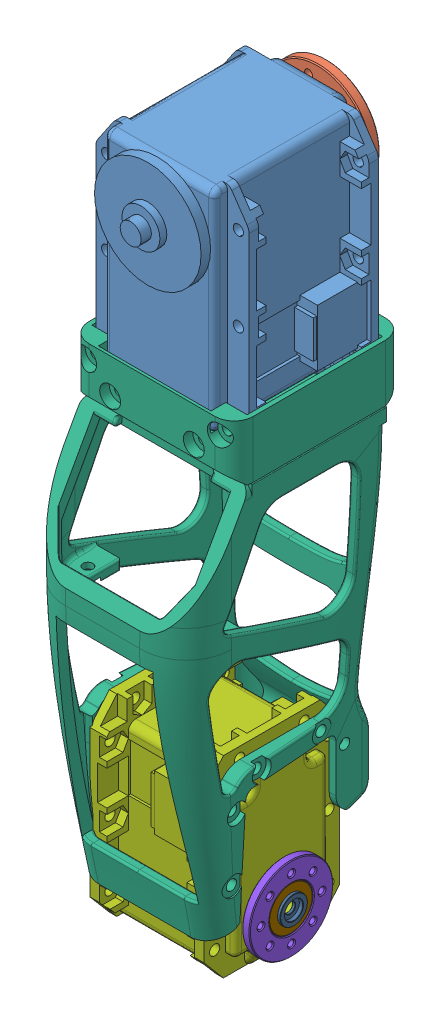
SolidWorks assembly arm_r2, configuration Default. Lengths in mm.
Overall size (47.19 187.91 62.65).
10 component instances, 10 part files, 22 mates.
Components (placement in the parent):
- MX-64T_step-1: MX-64T_step [Default] at (11.6566 50.7443 49.8736) size (40.2 62.1 50)
- HN05-I101_2017-1: HN05-I101_2017 [Default] at (11.6566 50.7443 26.3536) x (-0.978167 -0.207821 0) z (0.207821 -0.978167 0) size (28 3.8 28)
- MF128ZZ_2017-1: MF128ZZ_2017 [Default] at (11.6566 50.7443 30.0736) x (-0.981893 -0.189437 0) z (0.189437 -0.981893 0) size (14 3.48 14)
- RX64-CAP_2017-1: RX64-CAP_2017 [Default] at (11.6566 50.7443 26.5936) x (-0.772804 -0.634645 0) z (0 0 -1) size (9.5 9.5 2.2)
- WB_M2.5X8_2017-1: WB_M2.5X8_2017 [Default] at (11.6566 50.7443 24.2936) x (0 0 1) z (-0.923728 -0.383049 0) size (4.5 4.5 4.5)
- arm_upperarm-1: arm_upperarm [Default] at (-19.8184 -15.6443 22.4331) size (44.79 120.44 61.97)
- MX28_step-1: MX28_step [Default] at (53.0477 -67.7118 66.5106) x (0 0 -1) z (-1 0 0) size (35.6 50.71 42.6)
- MX28_HN07-i101-1: MX28_HN07-i101 [Default] at (30.6566 -105.0057 54.6029) x (0 -0.707328 0.706886) z (0 0.706886 0.707328) size (22 3.05 22)
- MF106ZZ-1: MF106ZZ [Défaut] at (30.5066 -105.0057 54.6029) x (0 0.837169 -0.546944) z (0 0.546944 0.837169) size (11.2 3 11.2)
- RX28-CAP-1: RX28-CAP [Défaut] at (30.5066 -105.0057 54.6029) x (0 -0.357314 -0.933984) z (1 0 0) size (7.2 7.2 1.8)
Mates (geometry in assembly coordinates):
- Concentric1: concentric aligned: cylinder of MX-64T_step-1 through (11.6566 50.7443 50.9736) axis (0 0 -1) radius 4; cylinder of HN05-I101_2017-1 through (11.6566 50.7443 26.3536) axis (0 0 -1) radius 6
- Coincident1: coincident aligned: cylinder of HN05-I101_2017-1 through (11.6566 50.7443 26.3536) axis (0 0 -1) radius 6; circle of MF128ZZ_2017-1
- Coincident2: coincident anti-aligned: plane of HN05-I101_2017-1 through (5.7876 49.4974 27.3536) normal (0 0 -1); plane of MF128ZZ_2017-1 through (4.7834 49.4183 27.3536) normal (0 0 1)
- Concentric2: concentric aligned: cylinder of MF128ZZ_2017-1 through (11.6566 50.7443 30.0736) axis (0 0 -1) radius 4; cylinder of RX64-CAP_2017-1 through (11.6566 50.7443 27.7936) axis (0 0 -1) radius 4
- Coincident3: coincident anti-aligned: plane of MF128ZZ_2017-1 through (7.7291 49.9866 26.5936) normal (0 0 -1); plane of RX64-CAP_2017-1 through (8.1017 47.825 26.5936) normal (0 0 1)
- Concentric3: concentric aligned: cylinder of RX64-CAP_2017-1 through (11.6566 50.7443 27.7936) axis (0 0 -1) radius 1.55; cylinder of WB_M2.5X8_2017-1 through (11.6566 50.7443 34.7936) axis (0 0 -1) radius 1.25
- Coincident4: coincident anti-aligned: plane of RX64-CAP_2017-1 through (10.3429 49.6654 26.7936) normal (0 0 -1); plane of WB_M2.5X8_2017-1 through (10.7948 52.8227 26.7936) normal (0 0 1)
- Coincident5: coincident anti-aligned: plane of MX-64T_step-1 through (11.6566 50.7443 30.0736) normal (0 0 -1); plane of MF128ZZ_2017-1 through (5.7653 49.6077 30.0736) normal (0 0 1)
- Concentric11: concentric anti-aligned: cylinder of MX-64T_step-1 through (-5.6434 10.7443 62.3736) axis (0 0 -1) radius 1.35; cylinder of arm_upperarm-1 through (-5.6434 10.7443 72.2736) axis (0 0 1) radius 2.75
- Concentric12: concentric anti-aligned: cylinder of MX-64T_step-1 through (0.6566 5.4443 49.8736) axis (0 0 -1) radius 1.35; cylinder of arm_upperarm-1 through (0.6566 5.4443 72.2736) axis (0 0 1) radius 2.75
- Distance3: distance = 0.8 mm anti-aligned: plane of MX-64T_step-1 through (11.6566 50.7443 66.8736) normal (0 0 1); plane of arm_upperarm-1 through (-8.7434 14.6443 67.6736) normal (0 0 -1)
- Concentric15: concentric aligned: cylinder of MX28_HN07-i101-1 through (30.8091 -105.0057 54.6029) axis (-1 0 0) radius 5; cylinder of MF106ZZ-1 through (30.5066 -105.0057 54.6029) axis (-1 0 0) radius 5
- Coincident16: coincident anti-aligned: plane of MX28_HN07-i101-1 through (29.9066 -105.0057 54.6029) normal (1 0 0); plane of MF106ZZ-1 through (29.9066 -100.8198 51.8681) normal (-1 0 0)
- Concentric16: concentric anti-aligned: cylinder of MF106ZZ-1 through (30.5066 -105.0057 54.6029) axis (-1 0 0) radius 3; cylinder of RX28-CAP-1 through (29.5066 -105.0057 54.6029) axis (1 0 0) radius 3
- Coincident17: coincident anti-aligned: plane of MF106ZZ-1 through (30.5066 -100.3175 51.54) normal (1 0 0); plane of RX28-CAP-1 through (30.5066 -106.2563 51.3339) normal (-1 0 0)
- Concentric17: concentric anti-aligned: cylinder of MX28_step-1 through (9.4941 -105.0057 54.6029) axis (1 0 0) radius 3; cylinder of MX28_HN07-i101-1 through (30.8091 -105.0057 54.6029) axis (-1 0 0) radius 6.25
- Coincident22: coincident anti-aligned: plane of MX28_step-1 through (27.5066 -105.0057 54.6029) normal (1 0 0); plane of MF106ZZ-1 through (27.5066 -102.4942 52.962) normal (-1 0 0)
- Coincident23: coincident anti-aligned: plane of arm_upperarm-1 through (-4.5434 -61.7057 36.6029) normal (1 0 0); plane of MX28_step-1 through (-4.5434 -105.0057 54.6029) normal (-1 0 0)
- Concentric18: concentric aligned: cylinder of arm_upperarm-1 through (36.8566 -92.5057 69.6029) axis (1 0 0) radius 1.35; cylinder of MX28_step-1 through (10.4566 -92.5057 69.6029) axis (1 0 0) radius 1.35
- Concentric19: concentric aligned: cylinder of arm_upperarm-1 through (36.8566 -69.2057 46.1029) axis (1 0 0) radius 1.35; cylinder of MX28_step-1 through (10.4566 -69.2057 46.1029) axis (1 0 0) radius 1.35
- Concentric20: concentric anti-aligned: cylinder of arm_upperarm-1 through (-13.5434 -75.5057 39.6029) axis (-1 0 0) radius 1.35; cylinder of MX28_step-1 through (10.4566 -75.5057 39.6029) axis (1 0 0) radius 1.35
- Concentric21: concentric anti-aligned: cylinder of arm_upperarm-1 through (-13.5434 -92.5057 69.6029) axis (-1 0 0) radius 1.35; cylinder of MX28_step-1 through (10.4566 -92.5057 69.6029) axis (1 0 0) radius 1.35
